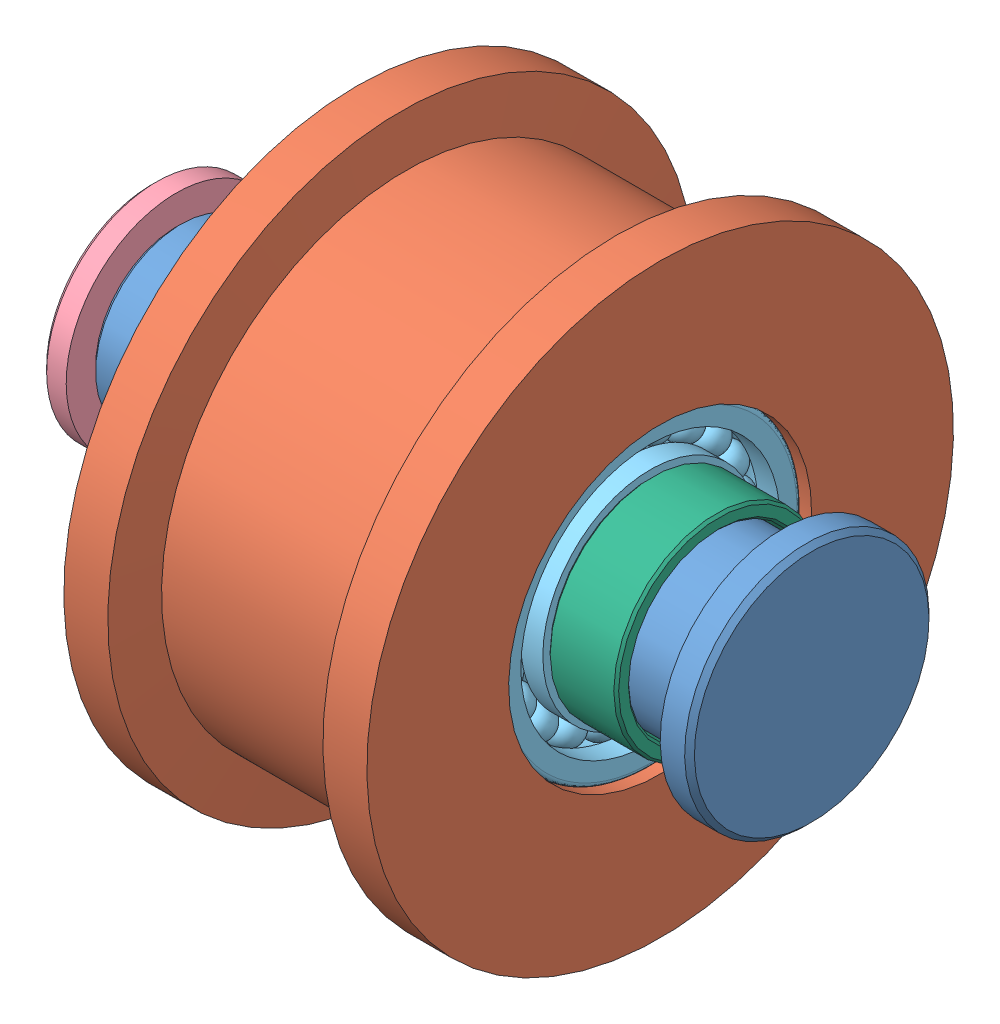
SolidWorks assembly 中臂托轮装配2, configuration 默认. Lengths in mm.
Overall size (135 126.08 126.08).
7 component instances, 6 part files, 19 mates.
Components (placement in the parent):
- 中臂托轮轴2-2: 中臂托轮轴2 [默认] at (-10903.1909 -1454.1078 2922.6408) x (-1 0 0) z (0 0.924225 0.381849) size (130 50 50)
- 中臂托轮-2: 中臂托轮 [默认] at (-10900.9278 1762.3162 -11333.5042) x (0 -0.998648 -0.051983) z (1 0 0) size (120 120 62)
- 中臂托轮挡圈-3: 中臂托轮挡圈 [默认] at (-6721.7675 1377.6787 -4007.9241) size (27 42 42)
- GB T892 B30挡圈-1: GB T892 B30挡圈 [默认] at (-6797.0125 1376.9166 -3929.5448) x (-1 0 0) z (0 -0.924225 -0.381849) size (5 45 45)
- deep groove ball bearings gb-3: deep groove ball bearings gb [Rolling bearings 6007 GB 276-94] at (-6707.0125 1376.9166 -3929.5448) size (14 62 62)
- deep groove ball bearings gb-4: deep groove ball bearings gb [Rolling bearings 6007 GB 276-94] at (-6751.0125 1376.9166 -3929.5448) size (14 62 62)
- 轴套35(2)-1: 轴套35(2) [Default] at (-6700.0125 1376.9166 -3929.5448) size (14 42 42)
Mates (geometry in assembly coordinates):
- 重合1: coincident: plane of ? through (-6733.0125 1395.2641 -3919.161) normal (1 0 0); plane of 中臂托轮-2 through (-6733.0125 1366.1526 -3888.2029) normal (-1 0 0)
- 重合2: coincident: plane of ? through (-6703.0125 1395.2641 -3919.161) normal (-1 0 0); plane of 中臂托轮-2 through (-6703.0125 1366.3605 -3892.1975) normal (1 0 0)
- 同心1: concentric: cylinder of ? through (-6707.2232 1367.7641 -3919.161) axis (-1 0 0) radius 27.5; cylinder of 中臂托轮-2 through (-6654.7494 1367.7641 -3919.161) axis (1 0 0) radius 31
- 同心3: concentric: cylinder of ? through (-6746.2232 1367.7641 -3919.161) axis (-1 0 0) radius 27.5; cylinder of 中臂托轮-2 through (-6654.7494 1367.7641 -3919.161) axis (1 0 0) radius 31
- 同心4: concentric: cylinder of 中臂托轮轴2-2 through (-6673.9723 1367.7641 -3919.161) axis (1 0 0) radius 15; cylinder of ? through (-6744.4839 1367.7641 -3919.161) axis (-1 0 0) radius 15
- 重合7: coincident: plane of 中臂托轮轴2-2 through (-6694.0125 1360.1271 -3900.6765) normal (-1 0 0); plane of ? through (-6694.0125 1382.7641 -3919.161) normal (1 0 0)
- 同心5: concentric: cylinder of 中臂托轮轴2-2 through (-6687.4723 1376.9166 -3929.5448) axis (1 0 0) radius 17.5; cylinder of 中臂托轮挡圈-3 through (-6875.1434 1376.9166 -3929.5448) axis (-1 0 0) radius 18
- 重合8: coincident: plane of ? through (-6742.0125 1386.9307 -3919.161) normal (-1 0 0); plane of 中臂托轮挡圈-3 through (-6742.0125 1367.6956 -3940.1609) normal (1 0 0)
- 重合9: coincident: plane of 中臂托轮轴2-2 through (-6797.0125 1370.6161 -3914.2951) normal (-1 0 0); plane of GB T892 B30挡圈-1 through (-6797.0125 1376.9166 -3929.5448) normal (1 0 0)
- 同心6: concentric: cylinder of 中臂托轮轴2-2 through (-6797.0125 1376.9166 -3929.5448) axis (-1 0 0) radius 2.5; cylinder of GB T892 B30挡圈-1 through (-6802.0125 1376.9166 -3929.5448) axis (1 0 0) radius 3.3
- 同心7: concentric: cylinder of 中臂托轮-2 through (-6665.7494 1376.9166 -3929.5448) axis (1 0 0) radius 31; cylinder of deep groove ball bearings gb-3 through (-6715.7232 1376.9166 -3929.5448) axis (-1 0 0) radius 31
- 同心8: concentric: cylinder of 中臂托轮轴2-2 through (-6687.4723 1376.9166 -3929.5448) axis (1 0 0) radius 17.5; cylinder of deep groove ball bearings gb-3 through (-6713.9839 1376.9166 -3929.5448) axis (-1 0 0) radius 17.5
- 重合10: coincident: plane of 中臂托轮-2 through (-6714.0125 1375.5131 -3902.5813) normal (1 0 0); plane of deep groove ball bearings gb-3 through (-6714.0125 1407.9166 -3929.5448) normal (-1 0 0)
- 同心9: concentric: cylinder of 中臂托轮-2 through (-6665.7494 1376.9166 -3929.5448) axis (1 0 0) radius 31; cylinder of deep groove ball bearings gb-4 through (-6759.7232 1376.9166 -3929.5448) axis (-1 0 0) radius 31
- 重合11: coincident: plane of 中臂托轮-2 through (-6744.0125 1375.3052 -3898.5867) normal (-1 0 0); plane of deep groove ball bearings gb-4 through (-6744.0125 1407.9166 -3929.5448) normal (1 0 0)
- 距离1: distance = 12 mm: plane of GB T892 B30挡圈-1 through (-6797.0125 1376.9166 -3929.5448) normal (1 0 0); plane of 中臂托轮挡圈-3 through (-6785.0125 1376.8481 -3950.5447) normal (-1 0 0)
- 重合13: coincident: plane of 中臂托轮挡圈-3 through (-6758.0125 1376.8481 -3950.5447) normal (1 0 0); plane of deep groove ball bearings gb-4 through (-6758.0125 1398.9166 -3929.5448) normal (-1 0 0)
- 重合14: coincident: plane of deep groove ball bearings gb-3 through (-6700.0125 1394.4166 -3929.5448) normal (1 0 0); plane of 轴套35(2)-1 through (-6700.0125 1376.9166 -3929.5448) normal (-1 0 0)
- 同心10: concentric: cylinder of 中臂托轮轴2-2 through (-6687.4723 1376.9166 -3929.5448) axis (1 0 0) radius 17.5; cylinder of 轴套35(2)-1 through (-6686.0125 1376.9166 -3929.5448) axis (-1 0 0) radius 18
